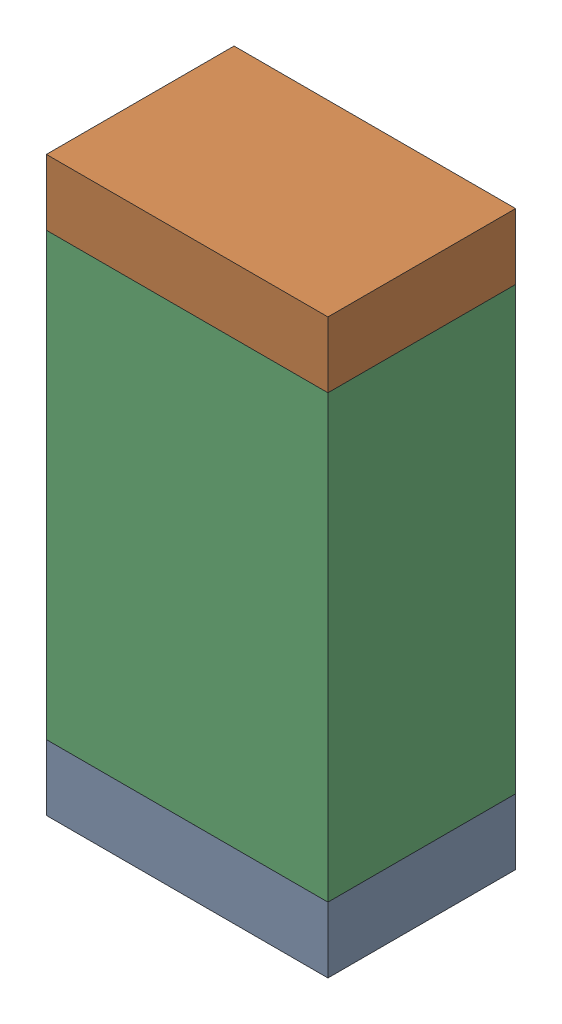
SolidWorks assembly R4, configuration Default. Lengths in mm.
Overall size (0.76 1.55 0.51).
6 component instances, 2 part files, 0 mates.
Components (placement in the parent):
- 822501776-1: 822501776 [Default] at (29.0324 13.7335 0) size (0.76 0.18 0.51)
  - Extruded_3-1: Extruded_3 [Default] at origin size (0.76 0.18 0.51)
- 822501776-2: 822501776 [Default] at (29.0324 15.1051 0) size (0.76 0.18 0.51)
  - Extruded_3-1: Extruded_3 [Default] at origin size (0.76 0.18 0.51)
- 822501912-1: 822501912 [Default] at (29.0324 14.4193 0) size (0.76 1.19 0.51)
  - Extruded_4-1: Extruded_4 [Default] at origin size (0.76 1.19 0.51)
